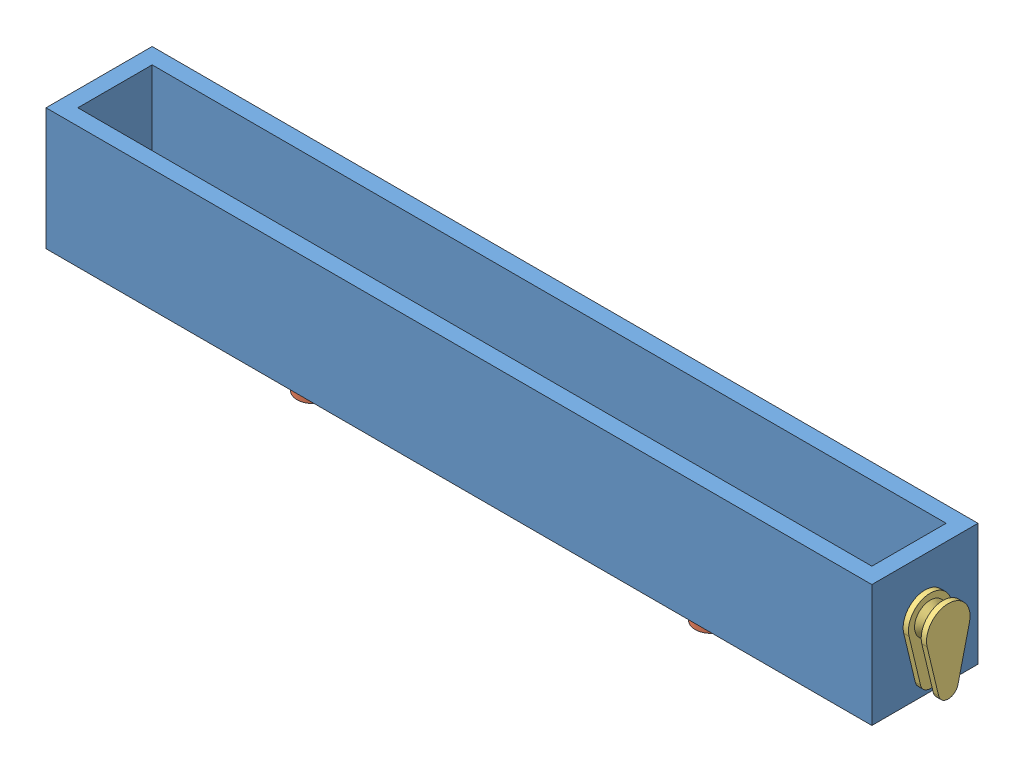
SolidWorks assembly 出绳点链接板（150）, configuration 默认. Lengths in mm.
Overall size (164.4 31 49).
5 component instances, 3 part files, 10 mates.
Components (placement in the parent):
- 出绳点链接板（150）-1: 出绳点链接板（150） [默认] at (-17.762 -8.3386 0) size (155.6 23 20)
- 柱塞螺丝M6-1: 柱塞螺丝M6 [默认] at (-55.262 -1.5986 0) x (0.837169 0 0.546944) z (0.546944 0 -0.837169) size (12 14.74 12)
- 柱塞螺丝M6-2: 柱塞螺丝M6 [默认] at (19.738 -1.5986 0) x (-0.837169 0 -0.546944) z (-0.546944 0 0.837169) size (12 14.74 12)
- 零件1^latest1-1: 零件1^latest1 [默认] at (-99.962 140.6589 -24.5142) x (0 0.000105 1) z (1 0 0) size (28.6 15.58 4.4)
- 零件1^latest1-2: 零件1^latest1 [默认] at (64.438 140.6589 24.5142) x (0 0.000105 -1) z (-1 0 0) size (28.6 15.58 4.4)
Mates (geometry in assembly coordinates):
- 重合1: coincident anti-aligned: plane of 出绳点链接板（150）-1 through (-17.762 -5.3386 0) normal (0 1 0); plane of 柱塞螺丝M6-1 through (-55.262 -5.3386 0) normal (0 -1 0)
- 同心2: concentric anti-aligned: cylinder of 出绳点链接板（150）-1 through (-55.262 -5.3386 0) axis (0 -1 0) radius 4; cylinder of 柱塞螺丝M6-1 through (-55.262 -8.3386 0) axis (0 1 0) radius 4
- 重合2: coincident anti-aligned: plane of 出绳点链接板（150）-1 through (-17.762 -5.3386 0) normal (0 1 0); plane of 柱塞螺丝M6-2 through (19.738 -5.3386 0) normal (0 -1 0)
- 同心3: concentric anti-aligned: cylinder of 出绳点链接板（150）-1 through (19.738 -5.3386 0) axis (0 -1 0) radius 4; cylinder of 柱塞螺丝M6-2 through (19.738 -8.3386 0) axis (0 1 0) radius 4
- 同心6: concentric anti-aligned: cylinder of 出绳点链接板（150）-1 through (64.438 4.6614 0) axis (-1 0 0) radius 2; cylinder of 零件1^latest1-1 through (-95.762 4.6614 0) axis (1 0 0) radius 1.5294
- 重合5: coincident anti-aligned: plane of 出绳点链接板（150）-1 through (-95.562 -5.3386 0) normal (-1 0 0); plane of 零件1^latest1-1 through (-95.562 4.6614 0) normal (1 0 0)
- 平行2: parallel anti-aligned: line of 出绳点链接板（150）-1 through (-95.562 14.6614 -10) axis (0 -1 0); line of 零件1^latest1-1 through (-97.762 -6.8153 -0.0004) axis (0 1 0)
- 同心7: concentric: cylinder of 出绳点链接板（150）-1 through (64.438 4.6614 0) axis (-1 0 0) radius 2; cylinder of 零件1^latest1-2 through (60.238 4.6614 0) axis (-1 0 0) radius 1.5294
- 重合7: coincident: plane of 出绳点链接板（150）-1 through (60.038 -5.3386 0) normal (1 0 0); plane of 零件1^latest1-2 through (60.038 4.6614 0) normal (-1 0 0)
- 平行3: parallel anti-aligned: line of 出绳点链接板（150）-1 through (60.038 14.6614 -10) axis (0 -1 0); line of 零件1^latest1-2 through (15.5817 62.238 -6.8153) axis (0 0 1)
